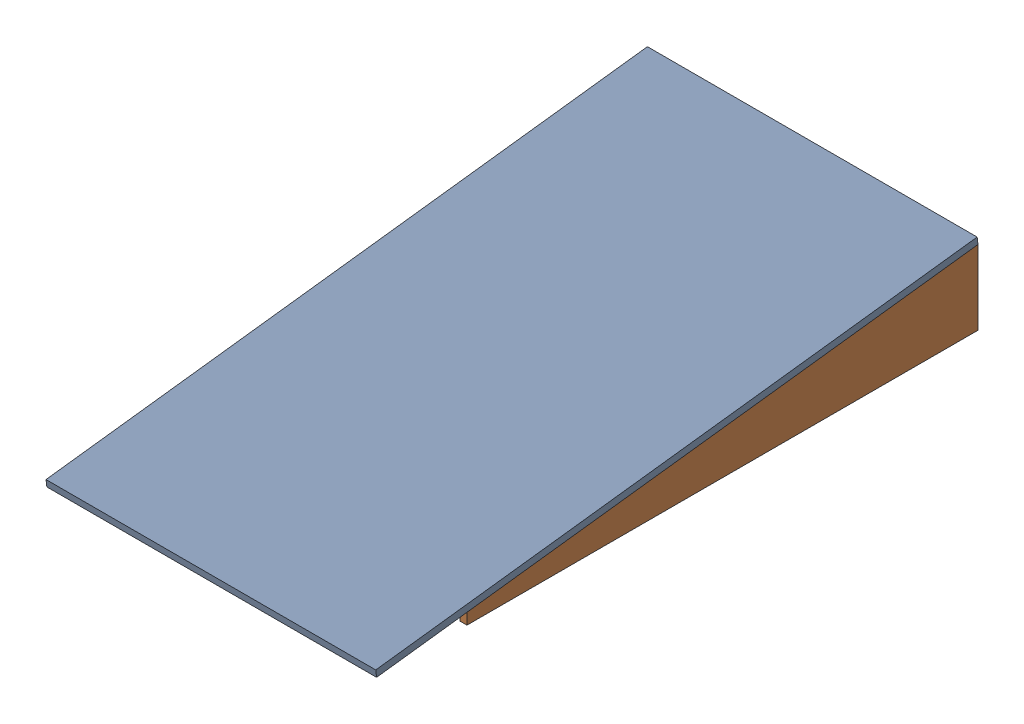
SolidWorks assembly GE-16138_ASM, configuration Default. Lengths in mm.
Overall size (606.42 149.25 1107.6).
4 component instances, 3 part files, 0 mates.
Components (placement in the parent):
- GE-16138-01-1: GE-16138-01 [Default] at origin size (606.42 149.03 1107.6)
- GE-16138-02-1: GE-16138-02 [Default] at (593.725 0 -103.7451) x (1 0 0) z (0 0.000201 1) size (12.7 136.64 939.8)
- GE-16138-02-2: GE-16138-02 [Default] at (0 0 -103.7451) x (1 0 0) z (0 0.000201 1) size (12.7 136.64 939.8)
- GE-16138-03-1: GE-16138-03 [Default] at (12.7 -0.2194 -1197.061) x (1 0 0) z (0 0.000201 1) size (581.02 134.94 12.7)
